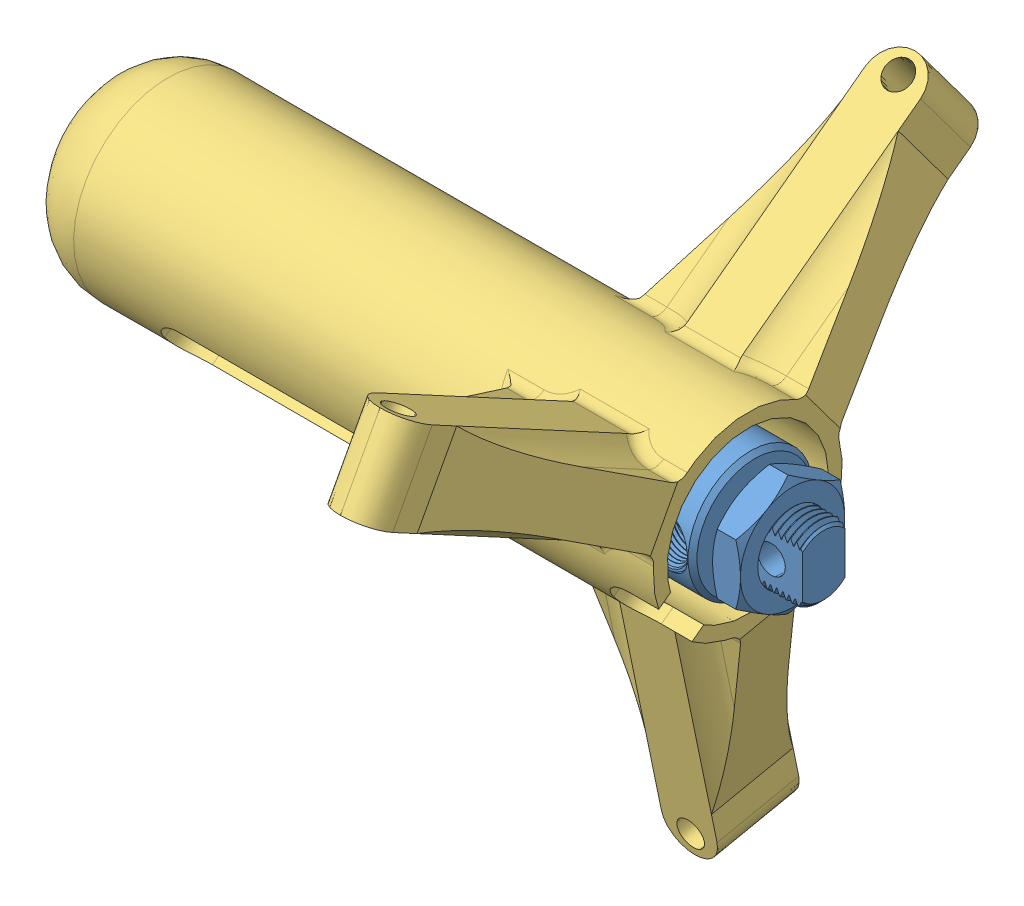
SolidWorks assembly Piston Assem, configuration Default. Lengths in mm.
Overall size (168.77 193.16 187.08).
3 component instances, 3 part files, 4 mates.
Components (placement in the parent):
- Piston Body-1: Piston Body [6498K654] at (48.3607 91.1672 114.2196) size (153.11 28.45 28.45)
- Piston Shaft-1: Piston Shaft [6498K654] at (48.3607 91.1672 114.2196) x (1 0 0) z (0 0.581675 -0.813421) size (70.22 8.18 8.17)
- Piston Cup CORRECT-2: Piston Cup CORRECT [Default] at (-32.5383 91.1672 114.2196) x (0 0.801624 0.597828) z (0 0.597828 -0.801624) size (150.78 147.64 120.93)
Mates (geometry in assembly coordinates):
- Concentric1: concentric: circle of Piston Body-1; cylinder of Piston Shaft-1 through (-73.8133 91.1672 114.2196) axis (-1 0 0) radius 3.9624
- LimitDistance1: limit distance = 15.748 mm: plane of Piston Body-1 through (-19.9653 91.1672 114.2196) normal (-1 0 0); plane of Piston Shaft-1 through (-35.7133 94.3955 116.5281) normal (-1 0 0)
- Concentric4: concentric: circle of Piston Shaft-1; circle of Piston Cup CORRECT-2
- Distance1: distance = 3.175 mm: plane of Piston Cup CORRECT-2 through (-32.5383 91.1672 114.2196) normal (-1 0 0); plane of Piston Shaft-1 through (-35.7133 94.3955 116.5281) normal (-1 0 0)
